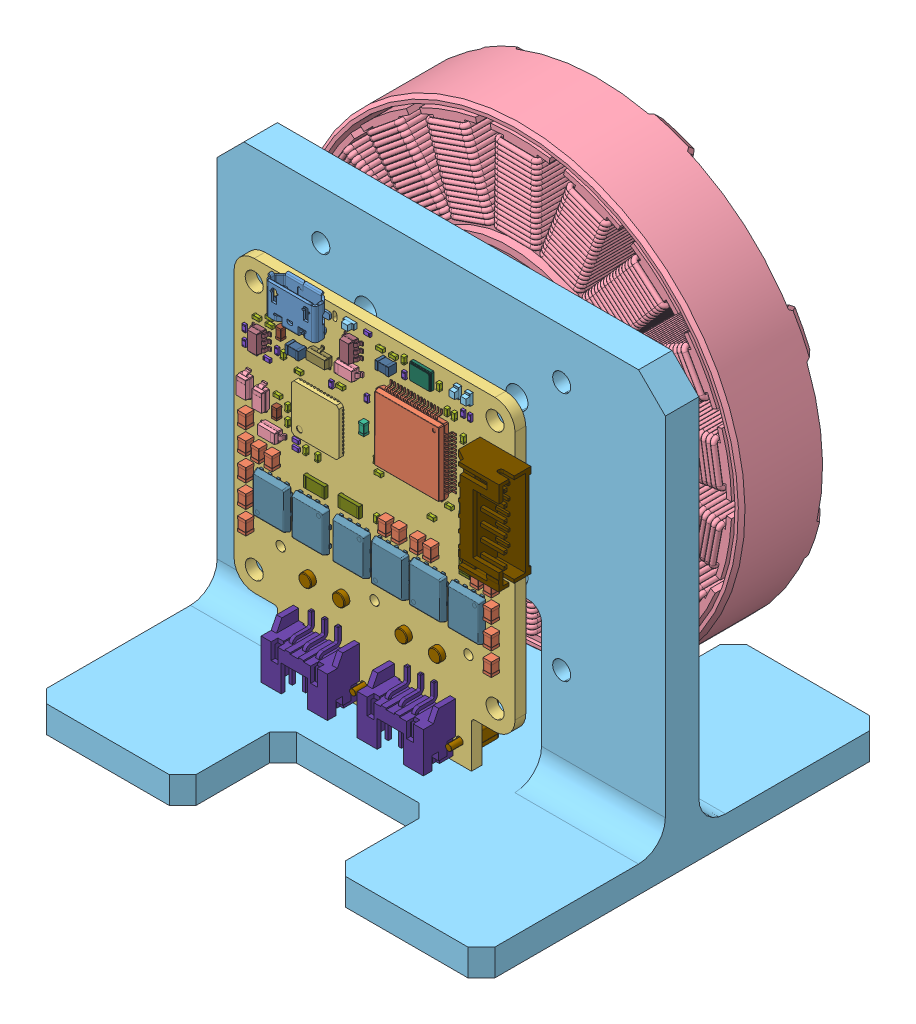
SolidWorks assembly Test Stand, configuration Default. Lengths in mm.
Overall size (94.48 94.48 61.9).
183 component instances, 23 part files, 4 mates.
Components (placement in the parent):
- Daedalus-1: Daedalus [Default] at (-191.1112 105.0384 20.0962) size (44.43 51.31 11.63)
  - Daedalus.step-1: Daedalus.step [Default] at origin size (44.43 51.31 11.63)
    - molex_0473460001.step-1: molex_0473460001.step [Default] at (133.8224 -76.8655 1.65) x (-1 0 0) z (0 1 0) size (7.98 2.76 5.43)
      - COMPOUND.step-1: COMPOUND.step [Default] at origin size (7.98 2.76 5.43)
    - LQFP-64_10x10mm_P0.5mm.step-1: LQFP-64_10x10mm_P0.5mm.step [Default] at (150.2843 -86.8057 1.65) x (0 -1 0) z (0 0 1) size (12 12 1.5)
      - SOLID.step-1: SOLID.step [Default] at origin size (12 12 1.5)
    - QFN127P600-8N.step-1: QFN127P600-8N.step [Default] at (135.871 -91.0039 1.65) x (0 1 0) z (0 0 1) size (7.15 7.15 0.75)
      - COMPOUND-0.step-1: COMPOUND-0.step [Default] at origin size (7.15 7.15 0.75)
    - D_SOD-123.step-1: D_SOD-123.step [Default] at (140.4976 -82.2096 1.65) size (3.8 1.6 1.25)
      - SOLID-1.step-1: SOLID-1.step [Default] at origin size (3.8 1.6 1.25)
    - LED_0603_1608Metric.step-1: LED_0603_1608Metric.step [Default] at (156.6516 -77.1197 1.65) x (0 1 0) z (0 0 1) size (1.6 0.8 1.1)
      - SOLID-2.step-1: SOLID-2.step [Default] at origin size (1.6 0.8 1.1)
    - C_0603_1608Metric.step-1: C_0603_1608Metric.step [Default] at (157.7975 -91.44 1.65) x (0 -1 0) z (0 0 1) size (1.6 0.8 0.8)
      - SOLID-3.step-1: SOLID-3.step [Default] at origin size (1.6 0.8 0.8)
    - C_0402_1005Metric.step-1: C_0402_1005Metric.step [Default] at (130.6322 -85.3769 1.65) x (0 -1 0) z (0 0 1) size (1 0.5 0.5)
      - SOLID-4.step-1: SOLID-4.step [Default] at origin size (1 0.5 0.5)
    - C_0402_1005Metric.step-2: C_0402_1005Metric.step [Default] at (126.6952 -82.5398 1.65) x (-1 0 0) z (0 0 1) size (1 0.5 0.5)
      - SOLID-4.step-1: SOLID-4.step [Default] at origin size (1 0.5 0.5)
    - R_0402_1005Metric.step-1: R_0402_1005Metric.step [Default] at (143.0426 -84.8411 1.65) x (0 -1 0) z (0 0 1) size (1 0.5 0.35)
      - SOLID-5.step-1: SOLID-5.step [Default] at origin size (1 0.5 0.35)
    - C_0402_1005Metric.step-3: C_0402_1005Metric.step [Default] at (147.0948 -77.337 1.65) size (1 0.5 0.5)
      - SOLID-4.step-1: SOLID-4.step [Default] at origin size (1 0.5 0.5)
    - Amass_XT30PW-M_pcb_solder.step-1: Amass_XT30PW-M_pcb_solder.step [Default] at (151.1541 -116.5924 -2.59) x (-1 0 0) z (0 0 -1) size (13.3 13.95 8.49)
      - SOLID-6.step-1: SOLID-6.step [Default] at origin size (13.3 13.95 8.49)
    - Amass_XT30PW-M_pcb_solder.step-2: Amass_XT30PW-M_pcb_solder.step [Default] at (136.8031 -116.5924 -2.59) x (-1 0 0) z (0 0 -1) size (13.3 13.95 8.49)
      - SOLID-6.step-1: SOLID-6.step [Default] at origin size (13.3 13.95 8.49)
    - R_0402_1005Metric.step-2: R_0402_1005Metric.step [Default] at (132.4508 -96.6368 1.65) x (-1 0 0) z (0 0 1) size (1 0.5 0.35)
      - SOLID-5.step-1: SOLID-5.step [Default] at origin size (1 0.5 0.35)
    - C_0402_1005Metric.step-4: C_0402_1005Metric.step [Default] at (128.6307 -82.55 1.65) size (1 0.5 0.5)
      - SOLID-4.step-1: SOLID-4.step [Default] at origin size (1 0.5 0.5)
    - C_0402_1005Metric.step-5: C_0402_1005Metric.step [Default] at (128.6307 -81.5442 1.65) size (1 0.5 0.5)
      - SOLID-4.step-1: SOLID-4.step [Default] at origin size (1 0.5 0.5)
    - C_0402_1005Metric.step-6: C_0402_1005Metric.step [Default] at (156.1898 -80.4962 1.65) x (0 -1 0) z (0 0 1) size (1 0.5 0.5)
      - SOLID-4.step-1: SOLID-4.step [Default] at origin size (1 0.5 0.5)
    - C_0402_1005Metric.step-7: C_0402_1005Metric.step [Default] at (157.5233 -82.8282 1.65) x (0 1 0) z (0 0 1) size (1 0.5 0.5)
      - SOLID-4.step-1: SOLID-4.step [Default] at origin size (1 0.5 0.5)
    - C_0402_1005Metric.step-8: C_0402_1005Metric.step [Default] at (144.9198 -93.5904 1.65) size (1 0.5 0.5)
      - SOLID-4.step-1: SOLID-4.step [Default] at origin size (1 0.5 0.5)
    - C_0402_1005Metric.step-9: C_0402_1005Metric.step [Default] at (144.5058 -91.9897 1.65) x (0 1 0) z (0 0 1) size (1 0.5 0.5)
      - SOLID-4.step-1: SOLID-4.step [Default] at origin size (1 0.5 0.5)
    - C_0402_1005Metric.step-10: C_0402_1005Metric.step [Default] at (155.1103 -80.4787 1.65) x (0 -1 0) z (0 0 1) size (1 0.5 0.5)
      - SOLID-4.step-1: SOLID-4.step [Default] at origin size (1 0.5 0.5)
    - C_0402_1005Metric.step-11: C_0402_1005Metric.step [Default] at (155.4448 -92.6154 1.65) x (-1 0 0) z (0 0 1) size (1 0.5 0.5)
      - SOLID-4.step-1: SOLID-4.step [Default] at origin size (1 0.5 0.5)
    - C_0402_1005Metric.step-12: C_0402_1005Metric.step [Default] at (145.1598 -77.337 1.65) size (1 0.5 0.5)
      - SOLID-4.step-1: SOLID-4.step [Default] at origin size (1 0.5 0.5)
    - C_0402_1005Metric.step-13: C_0402_1005Metric.step [Default] at (131.2824 -93.787 1.65) x (0 1 0) z (0 0 1) size (1 0.5 0.5)
      - SOLID-4.step-1: SOLID-4.step [Default] at origin size (1 0.5 0.5)
    - C_0402_1005Metric.step-14: C_0402_1005Metric.step [Default] at (133.9799 -96.078 1.65) x (0 1 0) z (0 0 1) size (1 0.5 0.5)
      - SOLID-4.step-1: SOLID-4.step [Default] at origin size (1 0.5 0.5)
    - C_0402_1005Metric.step-15: C_0402_1005Metric.step [Default] at (132.9334 -86.4108 1.65) x (-1 0 0) z (0 0 1) size (1 0.5 0.5)
      - SOLID-4.step-1: SOLID-4.step [Default] at origin size (1 0.5 0.5)
    - C_0402_1005Metric.step-16: C_0402_1005Metric.step [Default] at (131.2824 -91.8566 1.65) x (0 -1 0) z (0 0 1) size (1 0.5 0.5)
      - SOLID-4.step-1: SOLID-4.step [Default] at origin size (1 0.5 0.5)
    - C_0603_1608Metric.step-2: C_0603_1608Metric.step [Default] at (142.7886 -88.6663 1.65) x (0 1 0) z (0 0 1) size (1.6 0.8 0.8)
      - SOLID-3.step-1: SOLID-3.step [Default] at origin size (1.6 0.8 0.8)
    - C_0402_1005Metric.step-17: C_0402_1005Metric.step [Default] at (135.7681 -96.0703 1.65) x (0 -1 0) z (0 0 1) size (1 0.5 0.5)
      - SOLID-4.step-1: SOLID-4.step [Default] at origin size (1 0.5 0.5)
    - C_0402_1005Metric.step-18: C_0402_1005Metric.step [Default] at (129.8042 -91.059 1.65) size (1 0.5 0.5)
      - SOLID-4.step-1: SOLID-4.step [Default] at origin size (1 0.5 0.5)
    - C_0402_1005Metric.step-19: C_0402_1005Metric.step [Default] at (153.9443 -77.8002 1.65) x (0 1 0) z (0 0 1) size (1 0.5 0.5)
      - SOLID-4.step-1: SOLID-4.step [Default] at origin size (1 0.5 0.5)
    - C_0402_1005Metric.step-20: C_0402_1005Metric.step [Default] at (148.6511 -76.9989 1.65) x (0 -1 0) z (0 0 1) size (1 0.5 0.5)
      - SOLID-4.step-1: SOLID-4.step [Default] at origin size (1 0.5 0.5)
    - C_0402_1005Metric.step-21: C_0402_1005Metric.step [Default] at (139.1944 -85.2119 1.65) size (1 0.5 0.5)
      - SOLID-4.step-1: SOLID-4.step [Default] at origin size (1 0.5 0.5)
    - D_SOD-123.step-2: D_SOD-123.step [Default] at (127.6502 -92.3595 1.65) x (0 -1 0) z (0 0 1) size (3.8 1.6 1.25)
      - SOLID-1.step-1: SOLID-1.step [Default] at origin size (3.8 1.6 1.25)
    - D_SOD-123.step-3: D_SOD-123.step [Default] at (125.2677 -91.8616 1.65) x (0 -1 0) z (0 0 1) size (3.8 1.6 1.25)
      - SOLID-1.step-1: SOLID-1.step [Default] at origin size (3.8 1.6 1.25)
    - D_SOD-123.step-4: D_SOD-123.step [Default] at (129.0218 -96.0222 1.65) x (-1 0 0) z (0 0 1) size (3.8 1.6 1.25)
      - SOLID-1.step-1: SOLID-1.step [Default] at origin size (3.8 1.6 1.25)
    - LED_0603_1608Metric.step-2: LED_0603_1608Metric.step [Default] at (158.3516 -77.1197 1.65) x (0 1 0) z (0 0 1) size (1.6 0.8 1.1)
      - SOLID-2.step-1: SOLID-2.step [Default] at origin size (1.6 0.8 1.1)
    - L_0805_2012Metric.step-1: L_0805_2012Metric.step [Default] at (132.8369 -83.5203 1.65) size (2 1.25 1.25)
      - SOLID-7.step-1: SOLID-7.step [Default] at origin size (2 1.25 1.25)
    - L_0805_2012Metric.step-2: L_0805_2012Metric.step [Default] at (146.2948 -78.837 1.65) x (-1 0 0) z (0 0 1) size (2 1.25 1.25)
      - SOLID-7.step-1: SOLID-7.step [Default] at origin size (2 1.25 1.25)
    - L_0603_1608Metric.step-1: L_0603_1608Metric.step [Default] at (130.3579 -82.5449 1.65) x (0 1 0) z (0 0 1) size (1.6 0.8 0.8)
      - SOLID-8.step-1: SOLID-8.step [Default] at origin size (1.6 0.8 0.8)
    - L_0603_1608Metric.step-2: L_0603_1608Metric.step [Default] at (129.7483 -93.152 1.65) x (0 1 0) z (0 0 1) size (1.6 0.8 0.8)
      - SOLID-8.step-1: SOLID-8.step [Default] at origin size (1.6 0.8 0.8)
    - SOT-23.step-1: SOT-23.step [Default] at (136.3269 -82.7481 1.65) x (0 1 0) z (0 0 1) size (2.5 3 1.2)
      - SOLID-9.step-1: SOLID-9.step [Default] at origin size (2.5 3 1.2)
    - R_0402_1005Metric.step-3: R_0402_1005Metric.step [Default] at (124.7699 -84.8411 1.65) x (0 -1 0) z (0 0 1) size (1 0.5 0.35)
      - SOLID-5.step-1: SOLID-5.step [Default] at origin size (1 0.5 0.35)
    - R_0402_1005Metric.step-4: R_0402_1005Metric.step [Default] at (129.6314 -85.3796 1.65) x (0 -1 0) z (0 0 1) size (1 0.5 0.35)
      - SOLID-5.step-1: SOLID-5.step [Default] at origin size (1 0.5 0.35)
    - R_0402_1005Metric.step-5: R_0402_1005Metric.step [Default] at (126.2356 -87.2134 1.65) x (-1 0 0) z (0 0 1) size (1 0.5 0.35)
      - SOLID-5.step-1: SOLID-5.step [Default] at origin size (1 0.5 0.35)
    - R_0402_1005Metric.step-6: R_0402_1005Metric.step [Default] at (128.1762 -87.2134 1.65) x (-1 0 0) z (0 0 1) size (1 0.5 0.35)
      - SOLID-5.step-1: SOLID-5.step [Default] at origin size (1 0.5 0.35)
    - R_0402_1005Metric.step-7: R_0402_1005Metric.step [Default] at (124.7699 -86.7586 1.65) x (0 1 0) z (0 0 1) size (1 0.5 0.35)
      - SOLID-5.step-1: SOLID-5.step [Default] at origin size (1 0.5 0.35)
    - R_0402_1005Metric.step-8: R_0402_1005Metric.step [Default] at (137.7239 -85.6691 1.65) x (0 -1 0) z (0 0 1) size (1 0.5 0.35)
      - SOLID-5.step-1: SOLID-5.step [Default] at origin size (1 0.5 0.35)
    - R_0402_1005Metric.step-9: R_0402_1005Metric.step [Default] at (148.6511 -79.0079 1.65) x (0 1 0) z (0 0 1) size (1 0.5 0.35)
      - SOLID-5.step-1: SOLID-5.step [Default] at origin size (1 0.5 0.35)
    - R_0402_1005Metric.step-10: R_0402_1005Metric.step [Default] at (132.4508 -95.6158 1.65) size (1 0.5 0.35)
      - SOLID-5.step-1: SOLID-5.step [Default] at origin size (1 0.5 0.35)
    - R_0402_1005Metric.step-11: R_0402_1005Metric.step [Default] at (157.9931 -84.3178 1.65) x (-1 0 0) z (0 0 1) size (1 0.5 0.35)
      - SOLID-5.step-1: SOLID-5.step [Default] at origin size (1 0.5 0.35)
    - R_0402_1005Metric.step-12: R_0402_1005Metric.step [Default] at (157.4546 -79.6036 1.65) x (0 1 0) z (0 0 1) size (1 0.5 0.35)
      - SOLID-5.step-1: SOLID-5.step [Default] at origin size (1 0.5 0.35)
    - R_0402_1005Metric.step-13: R_0402_1005Metric.step [Default] at (158.4757 -79.6036 1.65) x (0 1 0) z (0 0 1) size (1 0.5 0.35)
      - SOLID-5.step-1: SOLID-5.step [Default] at origin size (1 0.5 0.35)
    - SOT-23-6.step-1: SOT-23-6.step [Default] at (127.2032 -84.8766 1.65) size (2.8 2.9 1.55)
      - SOLID-10.step-1: SOLID-10.step [Default] at origin size (2.8 2.9 1.55)
    - PowerFLAT_5x6.step-1: PowerFLAT_5x6.step [Default] at (129.1488 -104.9142 1.65) size (5.2 6.19 1.01)
      - COMPOUND-11.step-1: COMPOUND-11.step [Default] at origin size (5.2 6.19 1.01)
    - PowerFLAT_5x6.step-2: PowerFLAT_5x6.step [Default] at (146.8018 -104.9071 1.65) size (5.2 6.19 1.01)
      - COMPOUND-11.step-1: COMPOUND-11.step [Default] at origin size (5.2 6.19 1.01)
    - PowerFLAT_5x6.step-3: PowerFLAT_5x6.step [Default] at (152.5041 -104.8507 1.65) size (5.2 6.19 1.01)
      - COMPOUND-11.step-1: COMPOUND-11.step [Default] at origin size (5.2 6.19 1.01)
    - PowerFLAT_5x6.step-4: PowerFLAT_5x6.step [Default] at (134.9908 -104.9071 1.65) x (-1 0 0) z (0 0 1) size (5.2 6.19 1.01)
      - COMPOUND-11.step-1: COMPOUND-11.step [Default] at origin size (5.2 6.19 1.01)
    - PowerFLAT_5x6.step-5: PowerFLAT_5x6.step [Default] at (141.0868 -104.9127 1.65) x (-1 0 0) z (0 0 1) size (5.2 6.19 1.01)
      - COMPOUND-11.step-1: COMPOUND-11.step [Default] at origin size (5.2 6.19 1.01)
    - PowerFLAT_5x6.step-6: PowerFLAT_5x6.step [Default] at (158.308 -104.8619 1.65) x (-1 0 0) z (0 0 1) size (5.2 6.19 1.01)
      - COMPOUND-11.step-1: COMPOUND-11.step [Default] at origin size (5.2 6.19 1.01)
    - SOT-23-6.step-2: SOT-23-6.step [Default] at (140.9598 -79.1972 1.65) size (2.8 2.9 1.55)
      - SOLID-10.step-1: SOLID-10.step [Default] at origin size (2.8 2.9 1.55)
    - Crystal_SMD_3225-4Pin_3.2x2.5mm.step-1: Crystal_SMD_3225-4Pin_3.2x2.5mm.step [Default] at (151.3003 -77.7658 1.65) x (-1 0 0) z (0 0 1) size (3.2 2.5 0.64)
      - SOLID-12.step-1: SOLID-12.step [Default] at origin size (3.2 2.5 0.64)
    - R_1206_3216Metric.step-1: R_1206_3216Metric.step [Default] at (135.4607 -99.9668 1.65) size (3.2 1.6 0.55)
      - SOLID-13.step-1: SOLID-13.step [Default] at origin size (3.2 1.6 0.55)
    - R_1206_3216Metric.step-2: R_1206_3216Metric.step [Default] at (140.6169 -99.9668 1.65) x (-1 0 0) z (0 0 1) size (3.2 1.6 0.55)
      - SOLID-13.step-1: SOLID-13.step [Default] at origin size (3.2 1.6 0.55)
    - R_1206_3216Metric.step-3: R_1206_3216Metric.step [Default] at (157.9524 -98.7476 1.65) x (0 1 0) z (0 0 1) size (3.2 1.6 0.55)
      - SOLID-13.step-1: SOLID-13.step [Default] at origin size (3.2 1.6 0.55)
    - S3B-PH-SM4-TB.step-1: S3B-PH-SM4-TB.step [Default] at (151.1414 -124.9236 1.65) x (1 0 0) z (0 -1 0) size (9.9 4.8 8.6)
      - COMPOUND-14.step-1: COMPOUND-14.step [Default] at origin size (9.9 4.8 8.6)
    - S3B-PH-SM4-TB.step-2: S3B-PH-SM4-TB.step [Default] at (136.7904 -124.9288 1.65) x (1 0 0) z (0 -1 0) size (9.9 4.8 8.6)
      - COMPOUND-14.step-1: COMPOUND-14.step [Default] at origin size (9.9 4.8 8.6)
    - JST_PH_S6B-PH-K_1x06_P2.00mm_Horizontal.step-1: JST_PH_S6B-PH-K_1x06_P2.00mm_Horizontal.step [Default] at (161.1274 -93.538 1.65) x (0 1 0) z (0 0 1) size (13.9 7.6 8.25)
      - SOLID-15.step-1: SOLID-15.step [Default] at origin size (13.9 7.6 8.25)
    - TSSOP-14.step-1: TSSOP-14.step [Default] at (143.9164 -93.7666 -0.05) x (0 1 0) z (0 0 -1) size (6.43 7.25 1.1)
      - COMPOUND-16.step-1: COMPOUND-16.step [Default] at origin size (6.43 7.25 1.1)
    - C_0805_2012Metric.step-1: C_0805_2012Metric.step [Default] at (151.0563 -99.3572 1.65) x (0 1 0) z (0 0 1) size (2 1.25 1.25)
      - SOLID-17.step-1: SOLID-17.step [Default] at origin size (2 1.25 1.25)
    - C_0805_2012Metric.step-2: C_0805_2012Metric.step [Default] at (162.0799 -99.3676 1.65) x (0 1 0) z (0 0 1) size (2 1.25 1.25)
      - SOLID-17.step-1: SOLID-17.step [Default] at origin size (2 1.25 1.25)
    - C_0805_2012Metric.step-3: C_0805_2012Metric.step [Default] at (125.349 -95.9838 1.65) x (0 -1 0) z (0 0 1) size (2 1.25 1.25)
      - SOLID-17.step-1: SOLID-17.step [Default] at origin size (2 1.25 1.25)
    - C_0805_2012Metric.step-4: C_0805_2012Metric.step [Default] at (162.0774 -109.6721 1.65) x (0 1 0) z (0 0 1) size (2 1.25 1.25)
      - SOLID-17.step-1: SOLID-17.step [Default] at origin size (2 1.25 1.25)
    - C_0805_2012Metric.step-5: C_0805_2012Metric.step [Default] at (160.0987 -99.3595 1.65) x (0 1 0) z (0 0 1) size (2 1.25 1.25)
      - SOLID-17.step-1: SOLID-17.step [Default] at origin size (2 1.25 1.25)
    - C_0805_2012Metric.step-6: C_0805_2012Metric.step [Default] at (125.3769 -106.2637 1.65) x (0 1 0) z (0 0 1) size (2 1.25 1.25)
      - SOLID-17.step-1: SOLID-17.step [Default] at origin size (2 1.25 1.25)
    - C_0805_2012Metric.step-7: C_0805_2012Metric.step [Default] at (153.0248 -99.3549 1.65) x (0 1 0) z (0 0 1) size (2 1.25 1.25)
      - SOLID-17.step-1: SOLID-17.step [Default] at origin size (2 1.25 1.25)
    - C_0805_2012Metric.step-8: C_0805_2012Metric.step [Default] at (129.2962 -99.4207 1.65) x (0 1 0) z (0 0 1) size (2 1.25 1.25)
      - SOLID-17.step-1: SOLID-17.step [Default] at origin size (2 1.25 1.25)
    - C_0805_2012Metric.step-9: C_0805_2012Metric.step [Default] at (125.3769 -102.8474 1.65) x (0 -1 0) z (0 0 1) size (2 1.25 1.25)
      - SOLID-17.step-1: SOLID-17.step [Default] at origin size (2 1.25 1.25)
    - C_0805_2012Metric.step-10: C_0805_2012Metric.step [Default] at (146.3065 -99.4207 1.65) x (0 1 0) z (0 0 1) size (2 1.25 1.25)
      - SOLID-17.step-1: SOLID-17.step [Default] at origin size (2 1.25 1.25)
    - C_0805_2012Metric.step-11: C_0805_2012Metric.step [Default] at (162.0799 -106.2383 1.65) x (0 1 0) z (0 0 1) size (2 1.25 1.25)
      - SOLID-17.step-1: SOLID-17.step [Default] at origin size (2 1.25 1.25)
    - C_0805_2012Metric.step-12: C_0805_2012Metric.step [Default] at (125.3795 -109.6924 1.65) x (0 -1 0) z (0 0 1) size (2 1.25 1.25)
      - SOLID-17.step-1: SOLID-17.step [Default] at origin size (2 1.25 1.25)
    - C_0805_2012Metric.step-13: C_0805_2012Metric.step [Default] at (127.3277 -99.4207 1.65) x (0 1 0) z (0 0 1) size (2 1.25 1.25)
      - SOLID-17.step-1: SOLID-17.step [Default] at origin size (2 1.25 1.25)
    - C_0805_2012Metric.step-14: C_0805_2012Metric.step [Default] at (162.0799 -102.7989 1.65) x (0 -1 0) z (0 0 1) size (2 1.25 1.25)
      - SOLID-17.step-1: SOLID-17.step [Default] at origin size (2 1.25 1.25)
    - C_0805_2012Metric.step-15: C_0805_2012Metric.step [Default] at (125.3592 -99.4207 1.65) x (0 1 0) z (0 0 1) size (2 1.25 1.25)
      - SOLID-17.step-1: SOLID-17.step [Default] at origin size (2 1.25 1.25)
    - C_0805_2012Metric.step-16: C_0805_2012Metric.step [Default] at (148.275 -99.4207 1.65) x (0 1 0) z (0 0 1) size (2 1.25 1.25)
      - SOLID-17.step-1: SOLID-17.step [Default] at origin size (2 1.25 1.25)
    - LED_0603_1608Metric.step-3: LED_0603_1608Metric.step [Default] at (140.5738 -76.3676 1.65) x (-1 0 0) z (0 0 1) size (1.6 0.8 1.1)
      - SOLID-2.step-1: SOLID-2.step [Default] at origin size (1.6 0.8 1.1)
    - R_0402_1005Metric.step-14: R_0402_1005Metric.step [Default] at (143.1646 -76.3676 1.65) x (-1 0 0) z (0 0 1) size (1 0.5 0.35)
      - SOLID-5.step-1: SOLID-5.step [Default] at origin size (1 0.5 0.35)
    - C_0402_1005Metric.step-22: C_0402_1005Metric.step [Default] at (144.5514 -99.606 1.65) x (0 -1 0) z (0 0 1) size (1 0.5 0.5)
      - SOLID-4.step-1: SOLID-4.step [Default] at origin size (1 0.5 0.5)
    - C_0402_1005Metric.step-23: C_0402_1005Metric.step [Default] at (152.8317 -95.3389 1.65) x (-1 0 0) z (0 0 1) size (1 0.5 0.5)
      - SOLID-4.step-1: SOLID-4.step [Default] at origin size (1 0.5 0.5)
    - C_0402_1005Metric.step-24: C_0402_1005Metric.step [Default] at (160.6297 -96.8883 1.65) size (1 0.5 0.5)
      - SOLID-4.step-1: SOLID-4.step [Default] at origin size (1 0.5 0.5)
    - COMPOUND-18.step-1: COMPOUND-18.step [Default] at origin size (42.01 50.16 1.6)
- 6007-1: 6007 [Défaut] at (-48.0405 10.8066 -0.5669) x (-0.651824 -0.75837 0) z (0.75837 -0.651824 0) size (67 30 67)
- Stand-1: Stand [Default] at (-47.1525 -30.0141 9.2331) x (0 0 1) z (-1 0 0) size (60 64 67)
Mates (geometry in assembly coordinates):
- Coincident2: coincident anti-aligned: plane of 6007-1 through (-28.3466 12.2946 6.7331) normal (0 0 1); plane of Stand-1 through (-13.6526 33.9859 6.7331) normal (0 0 -1)
- Concentric3: concentric anti-aligned: cylinder of 6007-1 through (-58.4676 -1.3291 6.7331) axis (0 0 1) radius 1.65; cylinder of Stand-1 through (-58.4676 -1.3291 39.2331) axis (0 0 -1) radius 1.65
- Concentric5: concentric anti-aligned: cylinder of Daedalus-1/Daedalus.step-1/COMPOUND-18.step-1 through (-65.1526 26.6259 19.2962) axis (0 0 1) radius 1.35; cylinder of Stand-1 through (-65.1526 26.6259 39.2331) axis (0 0 -1) radius 1.35
- Parallel7: parallel aligned: plane of Daedalus-1/Daedalus.step-1/COMPOUND-18.step-1 through (-29.1659 29.6309 20.0962) normal (0 1 0); plane of Stand-1 through (-47.1526 33.9859 9.2331) normal (0 1 0)
